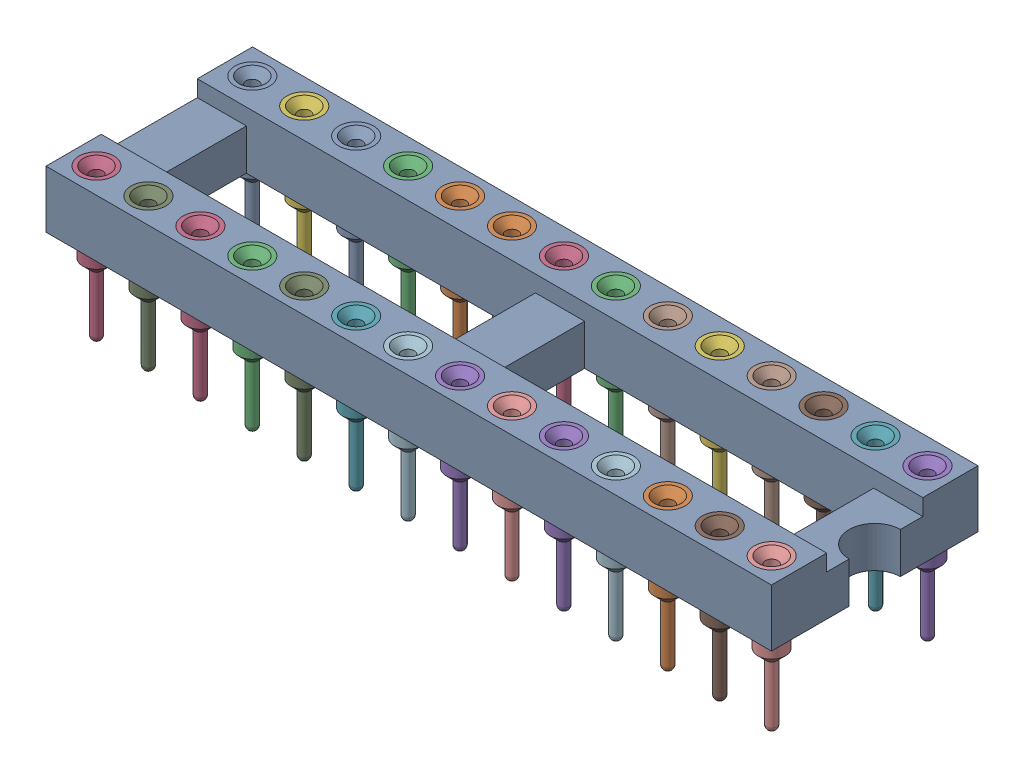
SolidWorks assembly dip28, configuration Default. Lengths in mm.
Overall size (35.48 7.37 10.1).
29 component instances, 2 part files, 0 mates.
Components (placement in the parent):
- dip28-1: dip28 [Default] at origin size (35.48 2.8 10.1)
- dip socket pin-1: dip socket pin [Default] at (-6.35 2.8 -3.81) size (1.7 7.37 1.7)
- dip socket pin-2: dip socket pin [Default] at (1.27 2.8 -3.81) size (1.7 7.37 1.7)
- dip socket pin-3: dip socket pin [Default] at (-16.51 2.8 3.81) size (1.7 7.37 1.7)
- dip socket pin-4: dip socket pin [Default] at (1.27 2.8 3.81) size (1.7 7.37 1.7)
- dip socket pin-5: dip socket pin [Default] at (6.35 2.8 -3.81) size (1.7 7.37 1.7)
- dip socket pin-6: dip socket pin [Default] at (13.97 2.8 -3.81) size (1.7 7.37 1.7)
- dip socket pin-7: dip socket pin [Default] at (3.81 2.8 -3.81) size (1.7 7.37 1.7)
- dip socket pin-8: dip socket pin [Default] at (-13.97 2.8 3.81) size (1.7 7.37 1.7)
- dip socket pin-9: dip socket pin [Default] at (16.51 2.8 3.81) size (1.7 7.37 1.7)
- dip socket pin-10: dip socket pin [Default] at (13.97 2.8 3.81) size (1.7 7.37 1.7)
- dip socket pin-11: dip socket pin [Default] at (-1.27 2.8 3.81) size (1.7 7.37 1.7)
- dip socket pin-12: dip socket pin [Default] at (-11.43 2.8 -3.81) size (1.7 7.37 1.7)
- dip socket pin-13: dip socket pin [Default] at (11.43 2.8 3.81) size (1.7 7.37 1.7)
- dip socket pin-14: dip socket pin [Default] at (-8.89 2.8 -3.81) size (1.7 7.37 1.7)
- dip socket pin-15: dip socket pin [Default] at (-1.27 2.8 -3.81) size (1.7 7.37 1.7)
- dip socket pin-16: dip socket pin [Default] at (16.51 2.8 -3.81) size (1.7 7.37 1.7)
- dip socket pin-17: dip socket pin [Default] at (-13.97 2.8 -3.81) size (1.7 7.37 1.7)
- dip socket pin-18: dip socket pin [Default] at (-3.81 2.8 3.81) size (1.7 7.37 1.7)
- dip socket pin-19: dip socket pin [Default] at (8.89 2.8 -3.81) size (1.7 7.37 1.7)
- dip socket pin-20: dip socket pin [Default] at (-6.35 2.8 3.81) size (1.7 7.37 1.7)
- dip socket pin-21: dip socket pin [Default] at (3.81 2.8 3.81) size (1.7 7.37 1.7)
- dip socket pin-22: dip socket pin [Default] at (11.43 2.8 -3.81) size (1.7 7.37 1.7)
- dip socket pin-23: dip socket pin [Default] at (8.89 2.8 3.81) size (1.7 7.37 1.7)
- dip socket pin-24: dip socket pin [Default] at (-16.51 2.8 -3.81) size (1.7 7.37 1.7)
- dip socket pin-25: dip socket pin [Default] at (-3.81 2.8 -3.81) size (1.7 7.37 1.7)
- dip socket pin-26: dip socket pin [Default] at (-8.89 2.8 3.81) size (1.7 7.37 1.7)
- dip socket pin-27: dip socket pin [Default] at (-11.43 2.8 3.81) size (1.7 7.37 1.7)
- dip socket pin-28: dip socket pin [Default] at (6.35 2.8 3.81) size (1.7 7.37 1.7)
